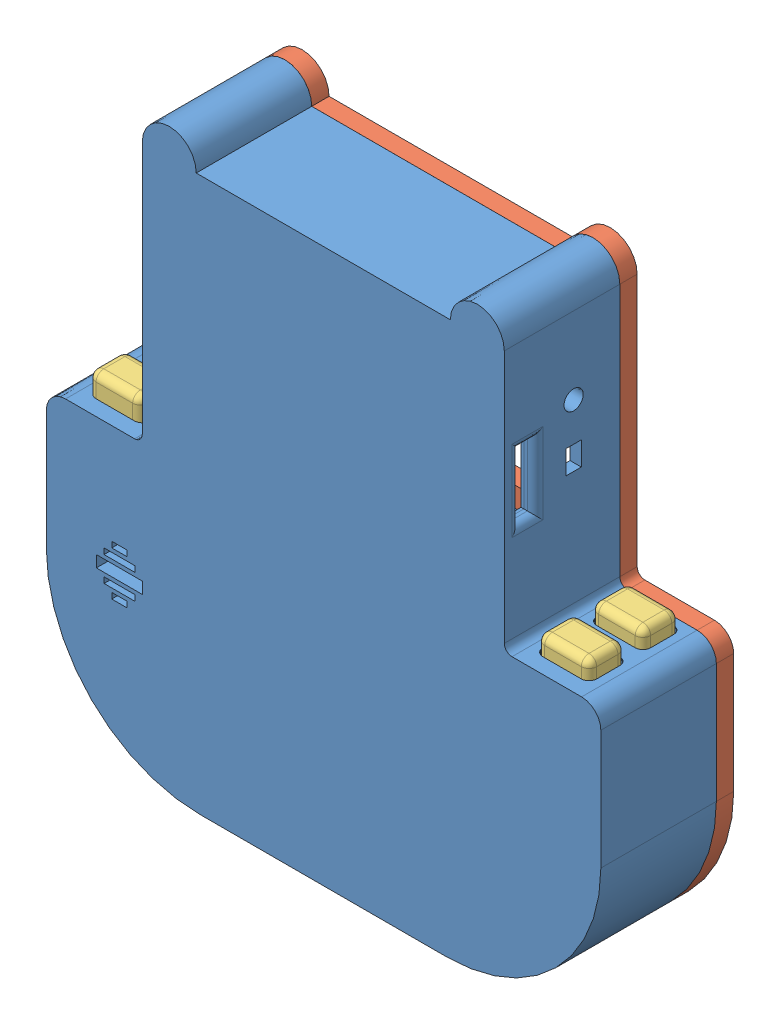
SolidWorks assembly Assem_AKIFBOY, configuration Default. Lengths in mm.
Overall size (144 150.77 34.5).
6 component instances, 3 part files, 15 mates.
Components (placement in the parent):
- AKIFBOY-1: AKIFBOY [Default] at (81.2506 170.9864 105.5985) x (-1 0 0) z (0 0 -1) size (144 150.77 30)
- AKIFBOY_cover-2: AKIFBOY_cover [Default] at (81.2521 171.2207 71.0985) size (144 150.77 30.5)
- AKIFBOY_button-1: AKIFBOY_button [Default] at (139.2506 141.7207 82.5985) x (-1 0 0) z (0 -1 0) size (16 12 10.2)
- AKIFBOY_button-2: AKIFBOY_button [Default] at (139.2506 141.7207 96.5985) x (1 0 0) z (0 -1 0) size (16 12 10.2)
- AKIFBOY_button-3: AKIFBOY_button [Default] at (23.2506 142.7207 82.5985) x (1 0 0) z (0 -1 0) size (16 12 10.2)
- AKIFBOY_button-4: AKIFBOY_button [Default] at (22.7506 142.7207 96.5985) x (1 0 0) z (0 -1 0) size (16 12 10.2)
Mates (geometry in assembly coordinates):
- Coincident5: coincident anti-aligned: plane of AKIFBOY-1 through (49.3221 68.2207 101.5985) normal (1 0 0); plane of AKIFBOY_cover-2 through (49.3221 61.2207 101.5985) normal (-1 0 0)
- Coincident6: coincident aligned: plane of AKIFBOY-1 through (81.2506 61.2207 75.5985) normal (0 -1 0); plane of AKIFBOY_cover-2 through (81.2521 61.2207 75.5985) normal (0 -1 0)
- Coincident7: coincident anti-aligned: plane of AKIFBOY-1 through (81.2506 170.9864 101.5985) normal (0 0 -1); plane of AKIFBOY_cover-2 through (81.2521 171.2207 101.5985) normal (0 0 1)
- Distance4: distance = 0.25 mm anti-aligned: plane of AKIFBOY-1 through (146.2506 124.1007 77.5985) normal (0 0 1); plane of AKIFBOY_button-1 through (146.0006 132.7207 77.8485) normal (0 0 -1)
- Distance8: distance = 0.5 mm anti-aligned: plane of AKIFBOY-1 through (81.2506 133.2207 75.5985) normal (0 -1 0); plane of AKIFBOY_button-1 through (139.2506 132.7207 82.5985) normal (0 1 0)
- Distance3: distance = 0.25 mm anti-aligned: plane of AKIFBOY-1 through (132.2506 124.1007 87.5985) normal (1 0 0); plane of AKIFBOY_button-1 through (132.5006 132.7207 87.3485) normal (-1 0 0)
- Distance2: distance = 0.25 mm anti-aligned: plane of AKIFBOY-1 through (146.2506 124.1007 91.5985) normal (0 0 1); plane of AKIFBOY_button-2 through (132.5006 132.7207 91.8485) normal (0 0 -1)
- Distance9: distance = 0.5 mm anti-aligned: plane of AKIFBOY-1 through (81.2506 133.2207 75.5985) normal (0 -1 0); plane of AKIFBOY_button-2 through (139.2506 132.7207 96.5985) normal (0 1 0)
- Distance1: distance = 0.25 mm anti-aligned: plane of AKIFBOY-1 through (132.2506 124.1007 101.5985) normal (1 0 0); plane of AKIFBOY_button-2 through (132.5006 132.7207 91.8485) normal (-1 0 0)
- Distance5: distance = 0.25 mm anti-aligned: plane of AKIFBOY_button-3 through (16.5006 133.7207 77.8485) normal (0 0 -1); plane of AKIFBOY-1 through (16.2506 124.1007 77.5985) normal (0 0 1)
- Distance6: distance = 0.5 mm anti-aligned: plane of AKIFBOY_button-3 through (23.2506 133.7207 82.5985) normal (0 1 0); plane of AKIFBOY-1 through (81.2506 133.2207 75.5985) normal (0 -1 0)
- Distance7: distance = 0.25 mm anti-aligned: plane of AKIFBOY_button-3 through (30.0006 133.7207 77.8485) normal (1 0 0); plane of AKIFBOY-1 through (30.2506 124.1007 87.5985) normal (-1 0 0)
- Distance10: distance = 0.25 mm anti-aligned: plane of AKIFBOY_button-4 through (16.0006 133.7207 91.8485) normal (0 0 -1); plane of AKIFBOY-1 through (16.2506 124.1007 91.5985) normal (0 0 1)
- Distance11: distance = 0.25 mm anti-aligned: plane of AKIFBOY_button-4 through (16.0006 133.7207 91.8485) normal (-1 0 0); plane of AKIFBOY-1 through (16.2506 124.1007 101.5985) normal (1 0 0)
- Distance12: distance = 0.5 mm anti-aligned: plane of AKIFBOY_button-4 through (22.7506 133.7207 96.5985) normal (0 1 0); plane of AKIFBOY-1 through (81.2506 133.2207 75.5985) normal (0 -1 0)
